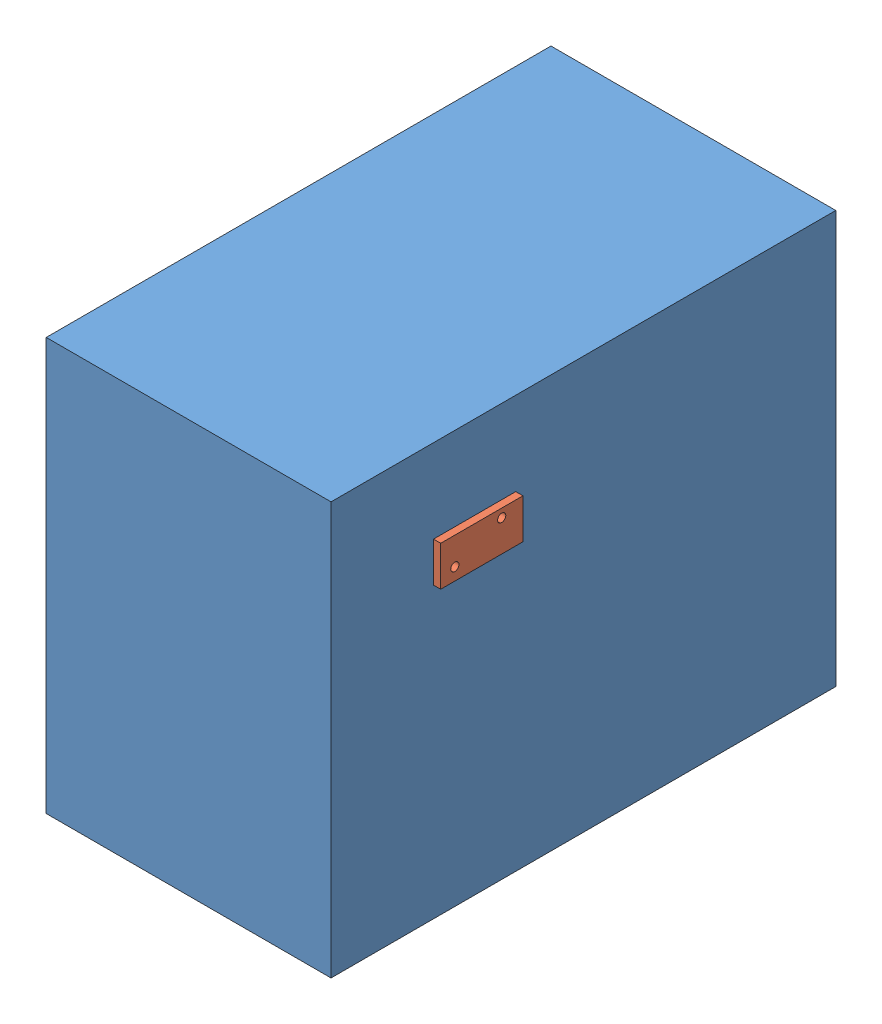
SolidWorks assembly test_mount_assem, configuration Default. Lengths in mm.
Overall size (102.87 145.26 177.8).
2 component instances, 2 part files, 0 mates.
Components (placement in the parent):
- unit-1: unit [Default] at (3.4197 118.1729 63.546) size (100.33 145.26 177.8)
- test_mount-1: test_mount [Default] at (53.5847 0 0) x (0 0 -1) z (1 0 0) size (28.98 14.03 2.54)
